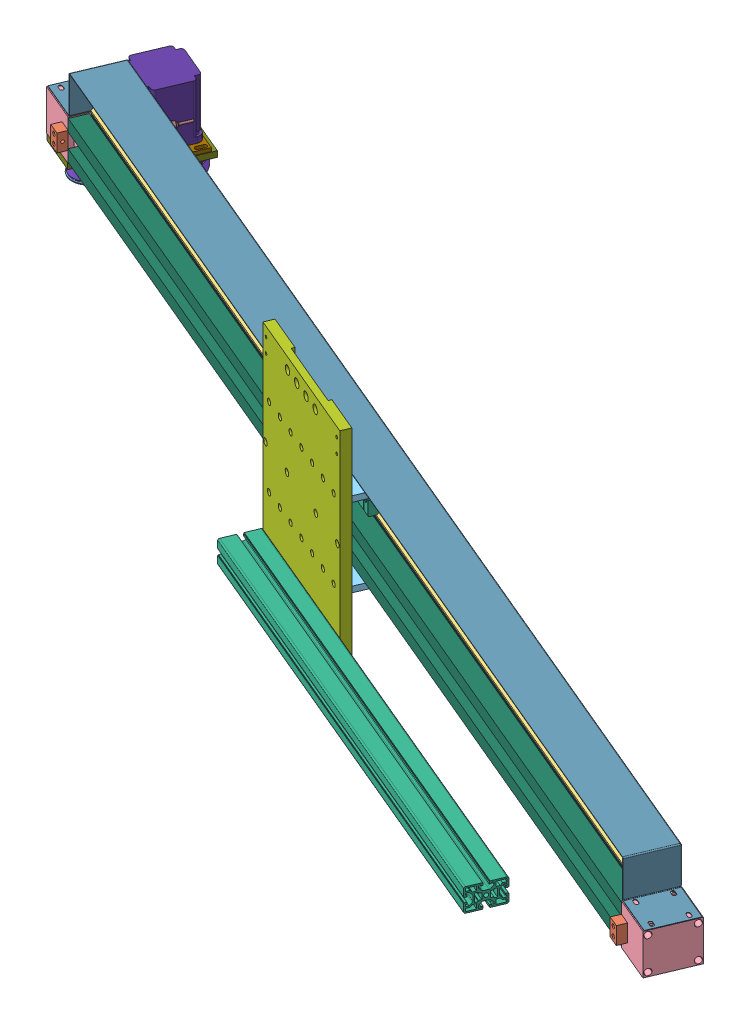
SolidWorks assembly 左右机械手, configuration 默认. Lengths in mm.
Overall size (1819.09 350 926.12).
51 component instances, 26 part files, 87 mates.
Components (placement in the parent):
- 高型EBJ42-S5M250-32-A-N-d20-1: 高型EBJ42-S5M250-32-A-N-d20 [默认] at (1053.1308 1493.0304 -55) x (-0.984765 0 -0.173888) z (0 -1 0) size (49.8 49.8 27)
- 高型连接块3-1: 高型连接块3 [默认] at (1008.7509 1510.0304 -14.007) x (0 -1 0) z (0.387964 0 -0.921675) size (30 20 15)
- 高型连接轴3-1: 高型连接轴3 [默认] at (1053.1308 1477.0304 -55) x (0 1 0) z (0.98909 0 0.14731) size (62 20 20)
- 高型连接块4-1: 高型连接块4 [默认] at (1085.3894 1510.0304 -41.4213) x (-0.387964 0 0.921675) z (-0.921675 0 -0.387964) size (80 70 70)
- 高型连接块7-1: 高型连接块7 [默认] at (97.9061 1447.5304 -446.8551) x (0.387964 0 -0.921675) z (0 -1 0) size (65 250 10)
- 高型一字连接铝型材-1: 高型一字连接铝型材 [默认<按加工>] at (-47.7584 1355.5304 -422.9991) x (0.921675 0 0.387964) z (0 -1 0) size (800 60 40)
- 高型连接块7-2: 高型连接块7 [默认] at (97.9061 1583.5304 -446.8551) x (0.387964 0 -0.921675) z (0 -1 0) size (65 250 10)
- 高型连接块6-1: 高型连接块6 [默认] at (85.2973 1510.5304 -416.9007) x (0.921675 0 0.387964) z (-0.387964 0 0.921675) size (250 350 16)
- 同步带1-1: 同步带1 [默认] at (-614.7461 1443.0304 -854.7143) x (0.921675 0 0.387964) z (0 -1 0) size (116 174.17 20)
- 高型EBJ42-S5M250-32-A-N-d20-2: 高型EBJ42-S5M250-32-A-N-d20 [默认] at (-670.4005 1526.9304 -780.4928) x (0.984766 0 -0.173886) z (0 1 0) size (49.8 49.8 27)
- 高型连接块8-1: 高型连接块8 [默认] at (-614.7461 1481.0304 -854.7143) x (-0.921675 0 -0.387964) z (-0.387964 0 0.921675) size (110 6 90)
- 高型连接轴2-1: 高型连接轴2 [默认] at (-670.4005 1433.0304 -780.4928) x (0 1 0) z (0.173886 0 0.984766) size (110 25 25)
- 高型EMZ3_12S-1: 高型EMZ3_12S [Default] at (-538.8861 1572.0304 -744.9573) x (-0.388749 0.906695 -0.163638) z (-0.387964 0 0.921675) size (21 21 67)
  - 高型EMZ3_12S_3-1: 高型EMZ3_12S_3 [Default] at (0 0 -17) x (1 0 0) z (0 0 -1) size (21 21 2)
  - 高型EMZ3_12S_5-1: 高型EMZ3_12S_5 [Default] at (0 0 -17) size (19.64 17.01 4.01)
  - 高型EMZ3_12S_3-2: 高型EMZ3_12S_3 [Default] at (0 0 -23.3) size (21 21 2)
  - 高型EMZ3_12S_5-2: 高型EMZ3_12S_5 [Default] at (0 0 -23.3) x (1 0 0) z (0 0 -1) size (19.64 17.01 4.01)
  - 高型EMZ3_12S_9-1: 高型EMZ3_12S_9 [Default] at origin size (12 12 67)
- 高型保护罩-1: 高型保护罩 [默认] at (176.456 1610.5036 -382.3271) x (0.921675 0 0.387964) z (0 1 0) size (1940 78 65.47)
- 高型一字铝型材-1: 高型一字铝型材 [默认<按加工>] at (-638.1419 1510.0304 -766.914) x (0 -1 0) z (0.921675 0 0.387964) size (66 80 1800)
- 高型连接块3-2: 高型连接块3 [默认] at (-668.6967 1510.0304 -720.1016) x (0 1 0) z (0.387964 0 -0.921675) size (30 20 15)
- 高型连接块4-2: 高型连接块4 [默认] at (-702.6591 1510.0304 -794.0715) x (0.387964 0 -0.921675) z (0.921675 0 0.387964) size (80 70 70)
- 高型连接块5-1: 高型连接块5 [默认] at (-630.2646 1465.0304 -817.8473) x (-0.921675 0 -0.387964) z (0 1 0) size (112 180 10)
- 高型电机3-1: 高型电机3 [默认] at (-614.7461 1481.0304 -854.7143) x (0.387964 0 -0.921675) z (0 1 0) size (90 90 145)
- 高型35胀套-1: 高型35胀套 [默认] at (-614.7461 1431.0304 -854.7143) x (-0.837169 0 -0.546944) z (0 1 0) size (35 35 20)
- 高型EBJ52-S5M250-32-B-V-d20-Z32-J24-1: 高型EBJ52-S5M250-32-B-V-d20-Z32-J24 [默认] at (-670.4005 1428.0304 -780.4928) x (0.997733 0 -0.067291) z (0 -1 0) size (55 55 36)
- 高型35胀套-2: 高型35胀套 [默认] at (-670.4005 1433.0304 -780.4928) x (-0.837169 0 -0.546944) z (0 1 0) size (35 35 20)
- 高型EBJ52-S5M250-72-A-H-d35-1: 高型EBJ52-S5M250-72-A-H-d35 [默认] at (-614.7461 1427.3994 -854.7143) x (0.998402 0 0.056508) z (0 -1 0) size (113.55 113.55 25)
- 高型IBC03_H30_L1500_6-1: 高型IBC03_H30_L1500_6 [Default] at (744.3698 1573.0304 -184.968) x (0.387964 0 -0.921675) z (0.921675 0 0.387964) size (20 18 1800)
- 高型IBC03_H30_L1500_6-3: 高型IBC03_H30_L1500_6 [Default] at (-361.6396 1447.0304 -650.5248) x (0.387964 0 -0.921675) z (-0.921675 0 -0.387964) size (20 18 1800)
- plain parallel keys-1: plain parallel keys [GB_CONNECTING_PIECE_KEYS_CSK 6X18] at (-668.6617 1503.0304 -770.6451) x (0 -1 0) z (0.173886 0 0.984766) size (18 6 6)
- deep groove ball bearings gb-3: deep groove ball bearings gb [Rolling bearings 6204 GB 276-94] at (-670.4005 1533.0304 -780.4928) x (0 1 0) z (-0.550825 0 0.834621) size (14 47 47)
- deep groove ball bearings gb-2: deep groove ball bearings gb [Rolling bearings 6204 GB 276-94] at (1053.1308 1484.0304 -55) x (0 1 0) z (-0.559067 0 0.829122) size (14 47 47)
- deep groove ball bearings gb-4: deep groove ball bearings gb [Rolling bearings 6204 GB 276-94] at (-670.4005 1485.0304 -780.4928) x (0 1 0) z (-0.546944 0 0.837169) size (14 47 47)
- deep groove ball bearings gb-1: deep groove ball bearings gb [Rolling bearings 6204 GB 276-94] at (1053.1308 1532.0304 -55) x (0 1 0) z (-0.903709 0 -0.428148) size (14 47 47)
- HGR20 滑块-1: HGR20 滑块 [默认] at (242.608 1561.0304 -396.2525) x (0.921675 0 0.387964) z (-0.387964 0 0.921675) size (97.48 36.05 44)
  - LM滑块-1: LM滑块 [默认] at (-242 0 0) x (0 0 -1) z (1 0 0) size (44 25.4 77.5)
  - 螺纹接头-1: 螺纹接头 [默认] at (-295.1321 19.3089 7.0344) x (-0.46194 0.191342 -0.866025) z (-0.745248 -0.613137 0.262049) size (15.11 19.64 23.4)
  - M6H-1: M6H [默认] at (-205.2216 7.1862 0) x (0 1 0) z (1 0 0) size (8 8 8)
- HGR20 滑块-2: HGR20 滑块 [默认] at (406.6661 1561.0304 -327.1949) x (0.921675 0 0.387964) z (-0.387964 0 0.921675) size (97.48 36.05 44)
  - LM滑块-1: LM滑块 [默认] at (-242 0 0) x (0 0 -1) z (1 0 0) size (44 25.4 77.5)
  - 螺纹接头-1: 螺纹接头 [默认] at (-295.1321 19.3089 7.0344) x (-0.46194 0.191342 -0.866025) z (-0.745248 -0.613137 0.262049) size (15.11 19.64 23.4)
  - M6H-1: M6H [默认] at (-205.2216 7.1862 0) x (0 1 0) z (1 0 0) size (8 8 8)
- HGR20 滑块-3: HGR20 滑块 [默认] at (406.6661 1459.0304 -327.1949) x (0.921675 0 0.387964) z (0.387964 0 -0.921675) size (97.48 36.05 44)
  - LM滑块-1: LM滑块 [默认] at (-242 0 0) x (0 0 -1) z (1 0 0) size (44 25.4 77.5)
  - 螺纹接头-1: 螺纹接头 [默认] at (-295.1321 19.3089 7.0344) x (-0.46194 0.191342 -0.866025) z (-0.745248 -0.613137 0.262049) size (15.11 19.64 23.4)
  - M6H-1: M6H [默认] at (-205.2216 7.1862 0) x (0 1 0) z (1 0 0) size (8 8 8)
- HGR20 滑块-4: HGR20 滑块 [默认] at (-203.4825 1459.0304 -584.0271) x (-0.921675 0 -0.387964) z (-0.387964 0 0.921675) size (97.48 36.05 44)
  - LM滑块-1: LM滑块 [默认] at (-242 0 0) x (0 0 -1) z (1 0 0) size (44 25.4 77.5)
  - 螺纹接头-1: 螺纹接头 [默认] at (-295.1321 19.3089 7.0344) x (-0.46194 0.191342 -0.866025) z (-0.745248 -0.613137 0.262049) size (15.11 19.64 23.4)
  - M6H-1: M6H [默认] at (-205.2216 7.1862 0) x (0 1 0) z (1 0 0) size (8 8 8)
Mates (geometry in assembly coordinates):
- 重合1: coincident anti-aligned: plane of 高型连接块7-2 through (200.5066 1573.5304 -368.4051) normal (-0.387964 0 0.921675); plane of 高型连接块6-1 through (85.2973 1510.5304 -416.9007) normal (0.387964 0 -0.921675)
- 重合2: coincident aligned: plane of 高型连接块7-2 through (-29.912 1573.5304 -465.3962) normal (-0.921675 0 -0.387964); plane of 高型连接块6-1 through (-36.1194 1685.5304 -450.6494) normal (-0.921675 0 -0.387964)
- 重合3: coincident anti-aligned: plane of 高型保护罩-1 through (176.456 1545.0304 -382.3271) normal (0 -1 0); plane of 高型连接块4-2 through (-653.6605 1545.0304 -730.0471) normal (0 1 0)
- 重合4: coincident anti-aligned: plane of 高型连接块4-2 through (-653.6605 1475.0304 -730.0471) normal (0 -1 0); plane of 高型连接块5-1 through (-630.2646 1475.0304 -817.8473) normal (0 1 0)
- 重合5: coincident aligned: plane of 高型一字铝型材-1 through (1036.3908 1510.0304 -105.4457) normal (0.387964 0 -0.921675); plane of 高型连接块4-2 through (-622.6234 1545.0304 -803.781) normal (0.387964 0 -0.921675)
- 重合6: coincident anti-aligned: plane of 高型连接块8-1 through (-614.7461 1481.0304 -854.7143) normal (0 1 0); plane of 高型电机3-1 through (-614.7461 1481.0304 -854.7143) normal (0 -1 0)
- 重合7: coincident aligned: plane of 高型连接块4-1 through (1005.3536 1545.0304 -31.7118) normal (-0.387964 0 0.921675); plane of 高型一字铝型材-1 through (1005.3536 1510.0304 -31.7118) normal (-0.387964 0 0.921675)
- 重合8: coincident aligned: plane of 高型连接块3-2 through (-653.6605 1495.0304 -730.0471) normal (0.921675 0 0.387964); plane of 高型连接块4-2 through (-638.1419 1510.0304 -766.914) normal (0.921675 0 0.387964)
- 重合9: coincident anti-aligned: plane of 高型一字铝型材-1 through (-638.1419 1510.0304 -766.914) normal (-0.921675 0 -0.387964); plane of 高型连接块4-2 through (-638.1419 1510.0304 -766.914) normal (0.921675 0 0.387964)
- 距离1: distance = 2 mm aligned: plane of 高型连接块4-2 through (-653.6605 1545.0304 -730.0471) normal (0 1 0); plane of 高型一字铝型材-1 through (1020.8722 1543.0304 -68.5787) normal (0 1 0)
- 同心1: concentric anti-aligned: cylinder of 高型连接块4-2 through (-670.4005 1458.0304 -780.4928) axis (0 1 0) radius 20; cylinder of 高型连接块5-1 through (-670.4005 1475.0304 -780.4928) axis (0 -1 0) radius 25
- 重合10: coincident aligned: plane of 高型保护罩-1 through (-687.7225 1545.0304 -829.556) normal (-0.921675 0 -0.387964); plane of 高型连接块4-2 through (-702.6591 1510.0304 -794.0715) normal (-0.921675 0 -0.387964)
- 同心2: concentric anti-aligned: circle of 高型连接块5-1; circle of 高型电机3-1
- 距离2: distance = 20 mm aligned: plane of 高型连接块3-2 through (-653.6605 1495.0304 -730.0471) normal (0 -1 0); plane of 高型连接块4-2 through (-653.6605 1475.0304 -730.0471) normal (0 -1 0)
- 同心3: concentric anti-aligned: circle of 高型连接块4-2; circle of 高型连接块5-1
- 重合11: coincident anti-aligned: plane of 高型连接块3-2 through (-662.8772 1510.0304 -733.9267) normal (0.387964 0 -0.921675); plane of 高型连接块4-2 through (-653.6605 1545.0304 -730.0471) normal (-0.387964 0 0.921675)
- 同心4: concentric anti-aligned: circle of 高型连接块8-1; circle of 高型连接块5-1
- 重合12: coincident anti-aligned: plane of 高型连接块4-1 through (1020.8722 1510.0304 -68.5787) normal (-0.921675 0 -0.387964); plane of 高型一字铝型材-1 through (1020.8722 1510.0304 -68.5787) normal (0.921675 0 0.387964)
- 重合13: coincident aligned: plane of 高型连接块4-1 through (1036.3908 1545.0304 -105.4457) normal (0 1 0); plane of 高型连接块4-2 through (-653.6605 1545.0304 -730.0471) normal (0 1 0)
- 同心5: concentric anti-aligned: circle of 高型连接轴2-1; circle of 高型连接块4-2
- 同心6: concentric anti-aligned: circle of 高型电机3-1; circle of 高型EBJ52-S5M250-72-A-H-d35-1
- 重合14: coincident aligned: plane of 高型电机3-1 through (-614.7461 1431.0304 -854.7143) normal (0 -1 0); plane of 高型EBJ52-S5M250-72-A-H-d35-1 through (-682.0677 1431.0304 -958.6846) normal (0 -1 0)
- 距离3: distance = 2 mm aligned: plane of 高型连接轴2-1 through (-680.2482 1543.0304 -778.7539) normal (0 1 0); plane of 高型连接块4-2 through (-653.6605 1545.0304 -730.0471) normal (0 1 0)
- 同心7: concentric aligned: circle of 高型连接轴2-1; circle of deep groove ball bearings gb-3
- 同心8: concentric aligned: circle of 高型连接轴2-1; circle of deep groove ball bearings gb-4
- 距离4: distance = 3 mm aligned: plane of deep groove ball bearings gb-4 through (-690.074 1478.0304 -793.346) normal (0 -1 0); plane of 高型连接块4-2 through (-653.6605 1475.0304 -730.0471) normal (0 -1 0)
- 距离5: distance = 22 mm aligned: plane of 高型EBJ42-S5M250-32-A-N-d20-2 through (-674.7954 1521.0304 -805.3821) normal (0 1 0); plane of 高型连接轴2-1 through (-680.2482 1543.0304 -778.7539) normal (0 1 0)
- 距离6: distance = 5 mm: cylinder of plain parallel keys-1 through (-668.14 1515.0304 -767.6908) axis (-0.173886 0 -0.984766) radius 3; cylinder of 高型连接轴2-1 through (-669.1833 1520.0304 -773.5994) axis (0.173886 0 0.984766) radius 3
- 重合15: coincident anti-aligned: plane of 高型连接轴2-1 through (-669.1833 1498.0304 -773.5994) normal (0.173886 0 0.984766); plane of plain parallel keys-1 through (-669.1833 1515.0304 -773.5994) normal (-0.173886 0 -0.984766)
- 重合16: coincident anti-aligned: plane of 高型连接轴2-1 through (-666.229 1498.0304 -774.1211) normal (-0.984766 0 0.173886); plane of plain parallel keys-1 through (-665.1857 1515.0304 -768.2125) normal (0.984766 0 -0.173886)
- 重合17: coincident aligned: plane of 高型EBJ42-S5M250-32-A-N-d20-2 through (-669.0685 1526.9304 -790.2018) normal (-0.984766 0 0.173886); plane of 高型连接轴2-1 through (-666.229 1498.0304 -774.1211) normal (-0.984766 0 0.173886)
- 同心9: concentric anti-aligned: circle of 高型EBJ42-S5M250-32-A-N-d20-2; circle of 高型连接轴2-1
- 距离7: distance = 3 mm aligned: plane of 高型EBJ52-S5M250-72-A-H-d35-1 through (-682.0677 1431.0304 -958.6846) normal (0 -1 0); plane of 高型EBJ52-S5M250-32-B-V-d20-Z32-J24-1 through (-670.4005 1428.0304 -780.4928) normal (0 -1 0)
- 同心10: concentric anti-aligned: cylinder of 高型连接轴2-1 through (-670.4005 1392.5653 -780.4928) axis (0 -1 0) radius 9.5; circle of 高型EBJ52-S5M250-32-B-V-d20-Z32-J24-1
- 重合18: coincident aligned: plane of 高型连接块4-2 through (-705.8572 1526.0304 -760.6983) normal (0 -1 0); plane of deep groove ball bearings gb-3 through (-690.0141 1526.0304 -793.4372) normal (0 -1 0)
- 重合19: coincident aligned: plane of deep groove ball bearings gb-1 through (1057.4123 1539.0304 -64.0371) normal (0 1 0); plane of 高型连接轴3-1 through (1051.6577 1539.0304 -45.1091) normal (0 1 0)
- 距离8: distance = 1.5 mm aligned: plane of 高型保护罩-1 through (-624.127 1545.0304 -802.7865) normal (0.387964 0 -0.921675); plane of 高型连接块4-2 through (-622.6234 1545.0304 -803.781) normal (0.387964 0 -0.921675)
- 平行1: parallel aligned: plane of 高型连接块4-2 through (-702.6591 1510.0304 -794.0715) normal (-0.921675 0 -0.387964); plane of 高型连接块5-1 through (-716.7952 1475.0304 -756.6226) normal (-0.921675 0 -0.387964)
- 同心11: concentric aligned: circle of deep groove ball bearings gb-1; circle of 高型连接轴3-1
- 同心12: concentric anti-aligned: circle of 高型EMZ3_12S-1/高型EMZ3_12S_9-1; circle of 高型保护罩-1
- 同心13: concentric aligned: circle of 高型连接块7-2; cylinder of 高型连接块6-1 through (175.8657 1578.5304 -361.4176) axis (-0.387964 0 0.921675) radius 2.75
- 平行2: parallel aligned: plane of 高型连接块8-1 through (-547.5655 1475.0304 -872.5474) normal (0.921675 0 0.387964); plane of 高型连接块5-1 through (-580.9787 1475.0304 -790.5913) normal (0.921675 0 0.387964)
- 重合20: coincident anti-aligned: plane of 高型连接块8-1 through (-614.7461 1475.0304 -854.7143) normal (0 -1 0); plane of 高型连接块5-1 through (-630.2646 1475.0304 -817.8473) normal (0 1 0)
- 同心14: concentric anti-aligned: circle of 高型连接块8-1; circle of 高型电机3-1
- 同心15: concentric anti-aligned: circle of 高型连接块8-1; circle of 高型电机3-1
- 重合21: coincident anti-aligned: plane of 高型一字连接铝型材-1 through (701.2202 1360.6304 -140.2781) normal (0.387964 0 -0.921675); plane of 高型连接块6-1 through (79.0899 1510.5304 -402.1539) normal (-0.387964 0 0.921675)
- 重合22: coincident aligned: plane of 高型连接轴2-1 through (-670.4005 1433.0304 -780.4928) normal (0 -1 0); plane of 高型35胀套-2 through (-670.4005 1433.0304 -780.4928) normal (0 -1 0)
- 重合23: coincident aligned: plane of 高型一字连接铝型材-1 through (-51.347 1339.0304 -414.4736) normal (-0.921675 0 -0.387964); plane of 高型连接块6-1 through (-36.1194 1685.5304 -450.6494) normal (-0.921675 0 -0.387964)
- 重合24: coincident aligned: plane of 高型一字连接铝型材-1 through (691.5599 1335.5304 -117.3284) normal (0 -1 0); plane of 高型连接块6-1 through (-36.1194 1335.5304 -450.6494) normal (0 -1 0)
- 同心16: concentric aligned: circle of 高型连接轴2-1; circle of 高型35胀套-2
- 重合25: coincident anti-aligned: circle of 高型电机3-1; circle of 高型35胀套-1
- 重合26: coincident anti-aligned: plane of 高型EMZ3_12S-1/高型EMZ3_12S_3-2 through (-537.6213 1568.4979 -767.535) normal (-0.387964 0 0.921675); plane of 高型保护罩-1 through (206.7172 1610.5036 -454.2177) normal (0.387964 0 -0.921675)
- 同心17: concentric aligned: circle of 复件 皮带4-4^装配体3-1; circle of 高型EBJ52-S5M250-72-A-H-d35-1
- 距离9: distance = 3 mm aligned: plane of 复件 皮带4-4^左右机械手-1 through (-584.7349 1453.0304 -808.6238) normal (0 1 0); plane of 高型EBJ52-S5M250-72-A-H-d35-1 through (-672.7047 1456.0304 -958.1547) normal (0 1 0)
- 同心18: concentric aligned: cylinder of 高型EBJ42-S5M250-32-A-N-d20-1 through (1053.1308 1525.0304 -55) axis (0 -1 0) radius 10; cylinder of 高型连接轴3-1 through (1053.1308 1436.5653 -55) axis (0 -1 0) radius 9.5
- 同心19: concentric aligned: cylinder of deep groove ball bearings gb-2 through (1053.1308 1477.059 -55) axis (0 -1 0) radius 10; cylinder of 高型连接轴3-1 through (1053.1308 1436.5653 -55) axis (0 -1 0) radius 10
- 重合27: coincident aligned: plane of deep groove ball bearings gb-2 through (1041.1085 1477.0304 -63.1065) normal (0 -1 0); plane of 高型连接轴3-1 through (1053.1308 1477.0304 -55) normal (0 -1 0)
- 重合29: coincident anti-aligned: plane of 高型EBJ42-S5M250-32-A-N-d20-1 through (1056.6086 1525.0304 -74.6953) normal (0 1 0); plane of deep groove ball bearings gb-1 through (1063.1923 1525.0304 -76.2372) normal (0 -1 0)
- 同心21: concentric anti-aligned: cylinder of deep groove ball bearings gb-2 through (1053.1308 1475.3197 -55) axis (0 -1 0) radius 23.5; cylinder of 高型连接块4-1 through (1053.1308 1480.0304 -55) axis (0 1 0) radius 23.5
- 距离11: distance = 4 mm anti-aligned: plane of 高型连接块4-1 through (1088.5875 1494.0304 -74.7945) normal (0 1 0); plane of 高型EBJ42-S5M250-32-A-N-d20-1 through (1053.1308 1498.0304 -55) normal (0 -1 0)
- 重合32: coincident anti-aligned: plane of 高型连接块3-1 through (1014.5704 1510.0304 -27.8321) normal (0.387964 0 -0.921675); plane of 高型连接块4-1 through (1005.3536 1545.0304 -31.7118) normal (-0.387964 0 0.921675)
- 同心22: concentric anti-aligned: cylinder of 高型连接块3-1 through (1014.5704 1517.5304 -27.8321) axis (-0.387964 0 0.921675) radius 3.5; cylinder of 高型连接块4-1 through (1045.6075 1517.5304 -101.5661) axis (0.387964 0 -0.921675) radius 2.5
- 同心23: concentric anti-aligned: cylinder of 高型连接块3-1 through (1014.5704 1502.5304 -27.8321) axis (-0.387964 0 0.921675) radius 3.5; cylinder of 高型连接块4-1 through (1045.6075 1502.5304 -101.5661) axis (0.387964 0 -0.921675) radius 2.5
- 重合33: coincident: plane of 高型一字铝型材-1 through (1020.8722 1543.0304 -68.5787) normal (0 1 0); plane of 高型IBC03_H30_L1500_6-1 through (-636.978 1543.0304 -769.6791) normal (0 -1 0)
- 宽度1: width: plane of 高型一字铝型材-1 through (1021.6674 1510.0304 -70.4678) normal (-0.387964 0 0.921675); plane of 高型一字铝型材-1 through (1020.077 1510.0304 -66.6897) normal (0.387964 0 -0.921675); plane of 高型IBC03_H30_L1500_6-1 through (-634.2623 1544.0304 -776.1308) normal (0.387964 0 -0.921675); plane of 高型IBC03_H30_L1500_6-1 through (-642.0216 1546.9314 -757.6973) normal (-0.387964 0 0.921675)
- 重合34: coincident aligned: plane of 高型一字铝型材-1 through (-638.1419 1510.0304 -766.914) normal (-0.921675 0 -0.387964); plane of 高型IBC03_H30_L1500_6-1 through (-634.358 1554.277 -775.9035) normal (-0.921675 0 -0.387964)
- 同心24: concentric aligned: cylinder of 高型连接块7-1 through (-11.4785 1442.5304 -457.6369) axis (-0.387964 0 0.921675) radius 2.5; cylinder of 高型连接块6-1 through (-17.6859 1442.5304 -442.8901) axis (-0.387964 0 0.921675) radius 5
- 同心25: concentric aligned: cylinder of 高型连接块7-1 through (20.7801 1442.5304 -444.0581) axis (-0.387964 0 0.921675) radius 2.5; cylinder of 高型连接块6-1 through (14.5727 1442.5304 -429.3113) axis (-0.387964 0 0.921675) radius 5
- 重合35: coincident anti-aligned: plane of 高型连接块7-1 through (200.5066 1437.5304 -368.4051) normal (-0.387964 0 0.921675); plane of 高型连接块6-1 through (85.2973 1510.5304 -416.9007) normal (0.387964 0 -0.921675)
- 重合36: coincident anti-aligned: plane of 高型一字铝型材-1 through (1020.8722 1477.0304 -68.5787) normal (0 -1 0); plane of 高型IBC03_H30_L1500_6-3 through (1017.3805 1477.0304 -60.2837) normal (0 1 0)
- 重合38: coincident aligned: plane of 高型IBC03_H30_L1500_6-1 through (1024.6562 1554.277 -77.5682) normal (0.921675 0 0.387964); plane of 高型IBC03_H30_L1500_6-3 through (1024.6562 1465.7838 -77.5682) normal (0.921675 0 0.387964)
- 重合39: coincident aligned: plane of 高型IBC03_H30_L1500_6-1 through (-642.0216 1546.9314 -757.6973) normal (-0.387964 0 0.921675); plane of 高型IBC03_H30_L1500_6-3 through (1016.9926 1473.1294 -59.362) normal (-0.387964 0 0.921675)
- 同心26: concentric aligned: circle of 同步带1-1; circle of 高型EBJ52-S5M250-32-B-V-d20-Z32-J24-1
- 重合40: coincident anti-aligned: plane of 高型IBC03_H30_L1500_6-1 through (-635.387 1561.0304 -773.4588) normal (0 1 0); plane of HGR20 滑块-1/LM滑块-1 through (-6.5148 1561.0304 -493.2715) normal (0 -1 0)
- 重合41: coincident anti-aligned: plane of 高型IBC03_H30_L1500_6-1 through (-641.9944 1558.2014 -757.7618) normal (-0.387964 0 0.921675); plane of HGR20 滑块-1/LM滑块-1 through (-7.5892 1556.9968 -490.7191) normal (0.387964 0 -0.921675)
- 同心27: concentric aligned: cylinder of 高型连接块7-2 through (-3.2348 1583.5304 -482.3763) axis (0 1 0) radius 5; cylinder of HGR20 滑块-1/LM滑块-1 through (-3.2348 1570.5304 -482.3763) axis (0 1 0) radius 2.067
- 同心28: concentric aligned: cylinder of 高型连接块7-2 through (29.9455 1583.5304 -468.4096) axis (0 1 0) radius 5; cylinder of HGR20 滑块-1/LM滑块-1 through (29.9455 1570.5304 -468.4096) axis (0 1 0) radius 2.067
- 重合42: coincident anti-aligned: plane of 高型连接块7-2 through (97.9061 1573.5304 -446.8551) normal (0 -1 0); plane of HGR20 滑块-1/LM滑块-1 through (-8.3651 1573.5304 -488.8758) normal (0 1 0)
- 同心29: concentric aligned: cylinder of 高型连接块7-2 through (173.2381 1583.5304 -442.8123) axis (0 1 0) radius 5; cylinder of HGR20 滑块-2/LM滑块-1 through (173.2381 1570.5304 -442.8123) axis (0 1 0) radius 2.067
- 同心30: concentric aligned: cylinder of 高型连接块7-2 through (160.8233 1583.5304 -413.3187) axis (0 1 0) radius 5; cylinder of HGR20 滑块-2/LM滑块-1 through (160.8233 1570.5304 -413.3187) axis (0 1 0) radius 2.067
- 重合43: coincident anti-aligned: plane of 高型连接块7-2 through (97.9061 1573.5304 -446.8551) normal (0 -1 0); plane of HGR20 滑块-2/LM滑块-1 through (168.4958 1573.5304 -450.2334) normal (0 1 0)
- 同心31: concentric: cylinder of 高型连接块7-1 through (-3.2348 1447.5304 -482.3763) axis (0 1 0) radius 2.75; cylinder of HGR20 滑块-4/LM滑块-1 through (-3.2348 1449.5304 -482.3763) axis (0 -1 0) radius 2.067
- 同心32: concentric: cylinder of 高型连接块7-1 through (9.18 1447.5304 -511.8699) axis (0 1 0) radius 2.75; cylinder of HGR20 滑块-4/LM滑块-1 through (9.18 1449.5304 -511.8699) axis (0 -1 0) radius 2.067
- 重合45: coincident anti-aligned: plane of 高型IBC03_H30_L1500_6-3 through (1023.6271 1459.0304 -75.1236) normal (0 -1 0); plane of HGR20 滑块-4/LM滑块-1 through (40.0298 1459.0304 -473.6793) normal (0 1 0)
- 重合46: coincident: plane of 高型IBC03_H30_L1500_6-3 through (1023.6271 1459.0304 -75.1236) normal (0 -1 0); plane of HGR20 滑块-3/LM滑块-1 through (162.2969 1459.0304 -427.9738) normal (0 1 0)
- 同心33: concentric: cylinder of 高型连接块7-1 through (206.4184 1447.5304 -428.8456) axis (0 1 0) radius 2.75; cylinder of HGR20 滑块-3/LM滑块-1 through (206.4184 1449.5304 -428.8456) axis (0 -1 0) radius 2.067
- 同心34: concentric anti-aligned: cylinder of 高型连接块7-1 through (194.0035 1447.5304 -399.352) axis (0 1 0) radius 2.75; cylinder of HGR20 滑块-3/LM滑块-1 through (194.0035 1449.5304 -399.352) axis (0 -1 0) radius 2.067
